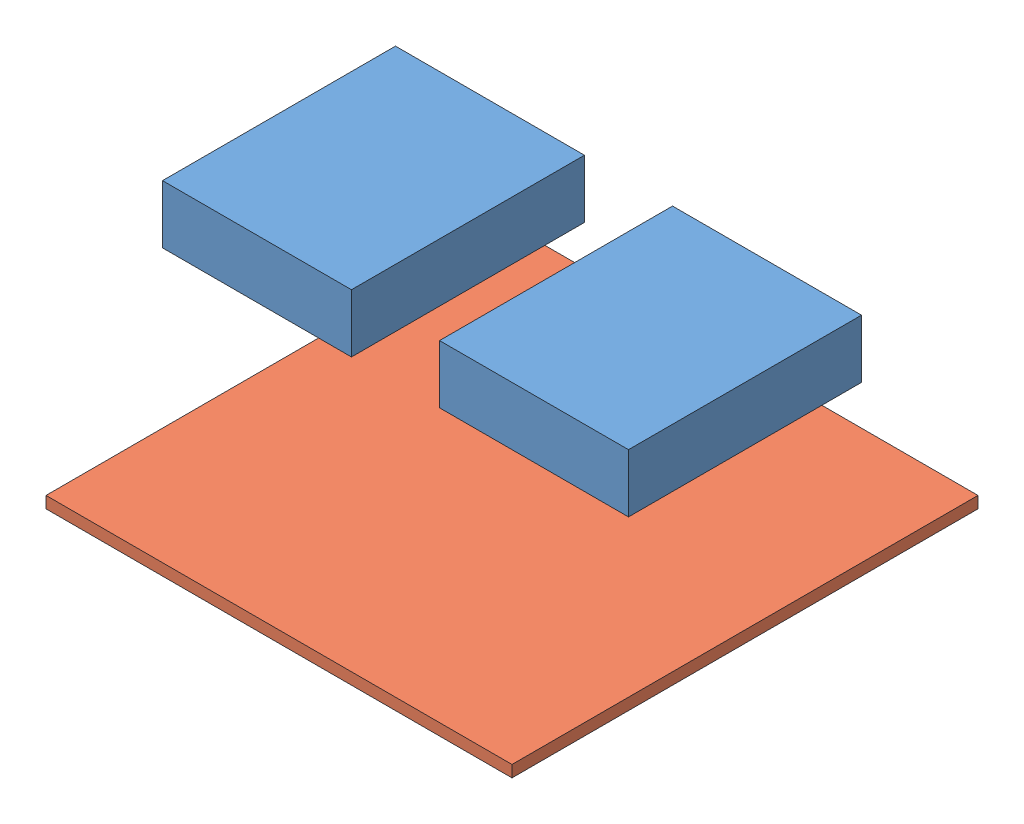
SolidWorks assembly boundary, configuration Default. Lengths in mm.
Overall size (2000 970 2000).
2 component instances, 2 part files, 6 mates.
Components (placement in the parent):
- optic_table^boundary-1: optic_table^boundary [Default] at (0 -250 0) size (2000 250 1000) (virtual)
- floor^boundary-1: floor^boundary [Default] at (0 -920 0) size (2000 50 2000) (virtual)
Mates (geometry in assembly coordinates):
- Coincident1: coincident aligned: plane of optic_table^boundary-1 through (0 -250 0) normal (0 0 1); plane of assembly through (0 0 0) normal (0 0 1)
- Coincident2: coincident aligned: plane of optic_table^boundary-1 through (0 0 0) normal (0 1 0); plane of assembly through (0 0 0) normal (0 1 0)
- Coincident3: coincident aligned: plane of optic_table^boundary-1 through (0 -250 0) normal (1 0 0); plane of assembly through (0 0 0) normal (1 0 0)
- Distance2: distance = 920 mm aligned: plane of floor^boundary-1 through (0 -920 0) normal (0 1 0); plane of optic_table^boundary-1 through (0 0 0) normal (0 1 0)
- Coincident6: coincident aligned: plane of floor^boundary-1 through (0 -920 0) normal (0 0 1); plane of assembly
- Coincident7: coincident aligned: plane of floor^boundary-1 through (0 -920 0) normal (1 0 0); plane of assembly
